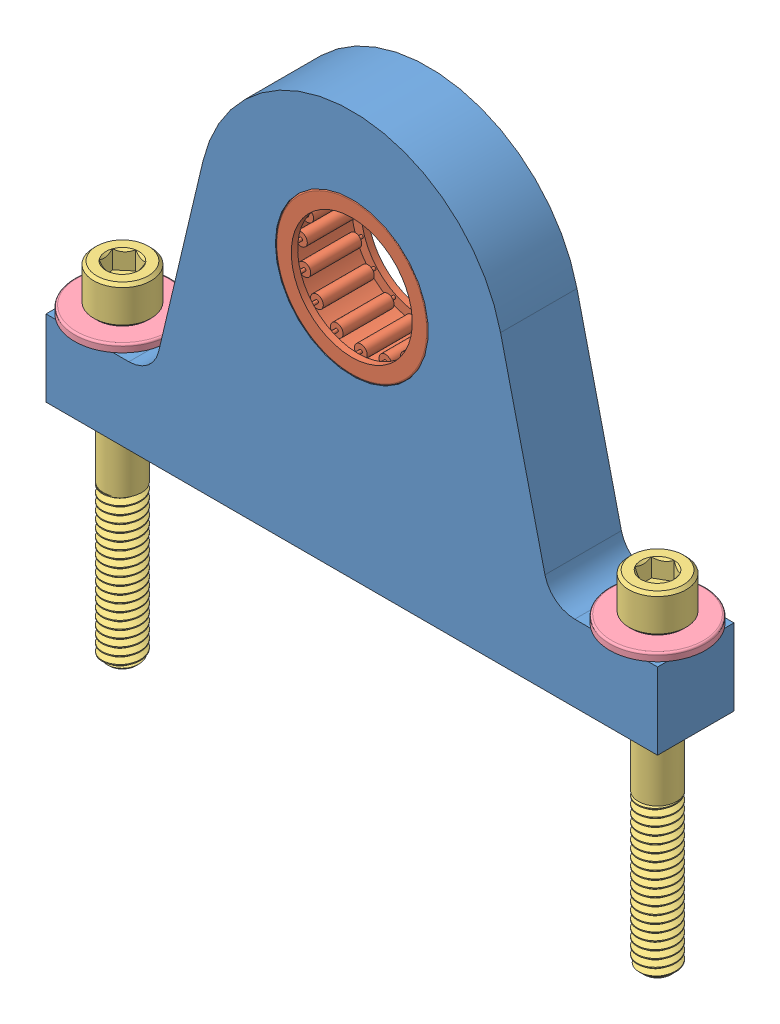
SolidWorks assembly Crosstree Bracket Assembly, configuration Default. Lengths in mm.
Overall size (104.78 104.64 15.88).
6 component instances, 4 part files, 10 mates.
Components (placement in the parent):
- Crosstree Bracket-1: Crosstree Bracket [Default] at (25.5889 69.8453 71.0296) size (101.6 67.31 12.7)
- 5905K26_Needle-Roller Bearing-1: 5905K26_Needle-Roller Bearing [5905K26] at (25.5889 69.8453 77.3796) x (-0.328056 0.944658 0) z (0 0 1) size (25.4 25.4 12.7)
- 90128A253_Zinc-Plated Alloy Steel Socket Head Screw-1: 90128A253_Zinc-Plated Alloy Steel Socket Head Screw [90128A253] at (-18.8611 19.6803 77.3796) x (-0.333308 0 0.942818) z (0 1 0) size (9.53 9.53 57.93)
- 90107A029_316 Stainless Steel Washer-2: 90107A029_316 Stainless Steel Washer [90107A029] at (-18.8611 41.2703 77.3796) x (1 0 0) z (0 1 0) size (15.88 15.88 1.27)
- 90128A253_Zinc-Plated Alloy Steel Socket Head Screw-2: 90128A253_Zinc-Plated Alloy Steel Socket Head Screw [90128A253] at (70.0389 19.6803 77.3796) x (1 0 0) z (0 1 0) size (9.53 9.53 57.93)
- 90107A029_316 Stainless Steel Washer-3: 90107A029_316 Stainless Steel Washer [90107A029] at (70.0389 41.2703 77.3796) x (1 0 0) z (0 1 0) size (15.88 15.88 1.27)
Mates (geometry in assembly coordinates):
- Coincident1: coincident aligned: circle of Crosstree Bracket-1; plane of 5905K26_Needle-Roller Bearing-1 through (13.5917 65.6789 83.7296) normal (0 0 1)
- Concentric1: concentric anti-aligned: cylinder of 5905K26_Needle-Roller Bearing-1 through (25.5889 69.8453 83.7296) axis (0 0 1) radius 12.7; cylinder of Crosstree Bracket-1 through (25.5889 69.8453 83.7296) axis (0 0 -1) radius 12.7
- Coincident3: coincident anti-aligned: plane of 90128A253_Zinc-Plated Alloy Steel Socket Head Screw-1 through (-22.9022 41.9053 75.951) normal (0 -1 0); plane of 90107A029_316 Stainless Steel Washer-2 through (-18.8611 41.9053 77.3796) normal (0 1 0)
- Concentric3: concentric aligned: circle of 90128A253_Zinc-Plated Alloy Steel Socket Head Screw-1; circle of 90107A029_316 Stainless Steel Washer-2
- Coincident4: coincident anti-aligned: plane of 90128A253_Zinc-Plated Alloy Steel Socket Head Screw-2 through (70.0389 41.9053 81.6659) normal (0 -1 0); plane of 90107A029_316 Stainless Steel Washer-3 through (70.0389 41.9053 77.3796) normal (0 1 0)
- Concentric4: concentric aligned: circle of 90128A253_Zinc-Plated Alloy Steel Socket Head Screw-2; circle of 90107A029_316 Stainless Steel Washer-3
- Coincident5: coincident anti-aligned: plane of Crosstree Bracket-1 through (-7.4311 40.6353 83.7296) normal (0 1 0); plane of 90107A029_316 Stainless Steel Washer-2 through (-18.8611 40.6353 77.3796) normal (0 -1 0)
- Concentric5: concentric aligned: circle of 90107A029_316 Stainless Steel Washer-2; circle of Crosstree Bracket-1
- Coincident6: coincident anti-aligned: plane of Crosstree Bracket-1 through (76.3889 40.6353 83.7296) normal (0 1 0); plane of 90107A029_316 Stainless Steel Washer-3 through (70.0389 40.6353 77.3796) normal (0 -1 0)
- Concentric6: concentric aligned: circle of 90107A029_316 Stainless Steel Washer-3; circle of Crosstree Bracket-1
